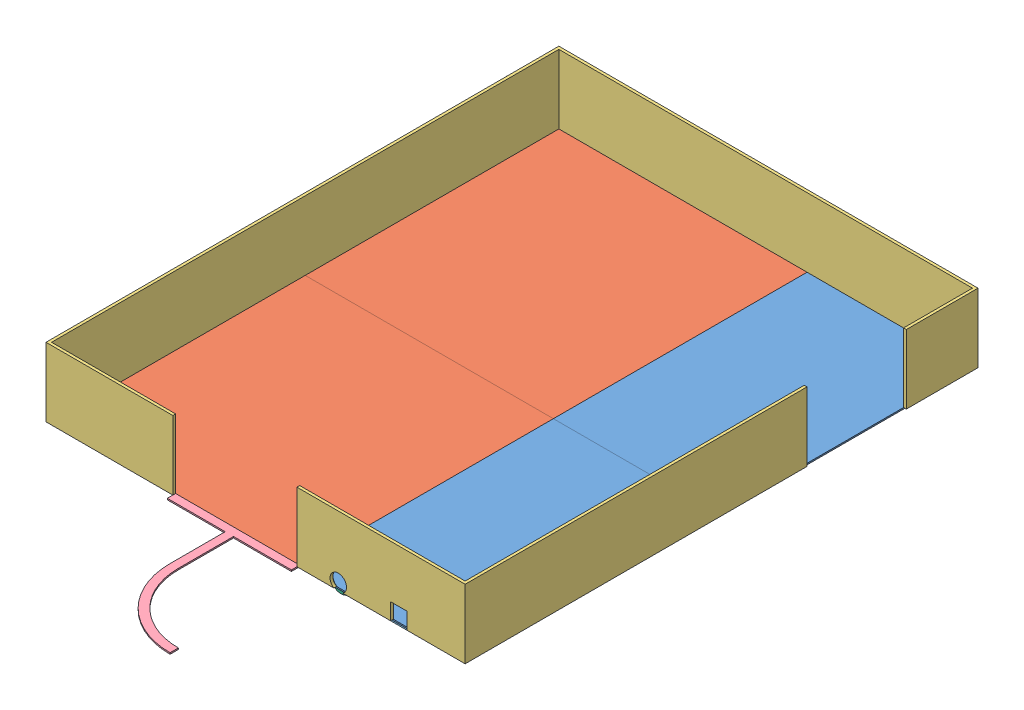
SolidWorks assembly Mosaic, configuration Default. Lengths in mm.
Overall size (1520 265 2360).
8 component instances, 6 part files, 20 mates.
Components (placement in the parent):
- Part2-1: Part2 [Default] at (315.7392 -5 1155.4589) size (600 5 920)
- Part2-2: Part2 [Default] at (315.7392 -5 2075.4589) size (600 5 920)
- Part2^Mosaic-1: Part2^Mosaic [Default] at (1396.6621 -5 82.6242) size (900 5 920) (virtual)
- Part2^Mosaic-2: Part2^Mosaic [Default] at (1396.6621 -5 -837.3758) size (900 5 920) (virtual)
- Part3^Mosaic-1: Part3^Mosaic [Default] at origin size (1520 250 1860) (virtual)
- Part4^Mosaic-1: Part4^Mosaic [Default] at (122.0061 -5 -12.8331) size (490 5 510) (virtual)
- Part5^Mosaic-1: Part5^Mosaic [Default] at (826.4444 -42.7357 2074.4589) x (1 0 0) z (0 -1 0) size (80 1 80) (virtual)
- Part6^Mosaic-1: Part6^Mosaic [Default] at (601.2126 136.7324 2074.4589) x (1 0 0) z (0 -1 0) size (80 1 80) (virtual)
Mates (geometry in assembly coordinates):
- Coincident1: coincident anti-aligned: plane of Part2-1 through (315.7392 0 1155.4589) normal (0 0 1); plane of Part2-2 through (315.7392 0 1155.4589) normal (0 0 -1)
- Coincident2: coincident aligned: plane of Part2-1 through (315.7392 -5 1155.4589) normal (0 -1 0); plane of Part2-2 through (315.7392 -5 2075.4589) normal (0 -1 0)
- Coincident3: coincident aligned: plane of Part2-1 through (315.7392 0 1155.4589) normal (-1 0 0); plane of Part2-2 through (315.7392 0 2075.4589) normal (-1 0 0)
- Coincident4: coincident anti-aligned: plane of Part2-2 through (315.7392 0 2075.4589) normal (-1 0 0); plane of Part2^Mosaic-1 through (315.7392 0 1155.4589) normal (1 0 0)
- Coincident5: coincident aligned: plane of Part2-2 through (315.7392 0 2075.4589) normal (0 1 0); plane of Part2^Mosaic-1 through (1396.6621 0 82.6242) normal (0 1 0)
- Coincident6: coincident aligned: plane of Part2-2 through (315.7392 0 2075.4589) normal (0 0 1); plane of Part2^Mosaic-1 through (-584.2608 0 2075.4589) normal (0 0 1)
- Coincident7: coincident anti-aligned: plane of Part2-1 through (315.7392 0 1155.4589) normal (-1 0 0); plane of Part2^Mosaic-2 through (315.7392 0 235.4589) normal (1 0 0)
- Coincident8: coincident aligned: plane of Part2-1 through (315.7392 0 1155.4589) normal (0 1 0); plane of Part2^Mosaic-2 through (1396.6621 0 -837.3758) normal (0 1 0)
- Coincident10: coincident anti-aligned: plane of Part2^Mosaic-1 through (-584.2608 0 1155.4589) normal (0 0 -1); plane of Part2^Mosaic-2 through (-584.2608 0 1155.4589) normal (0 0 1)
- Coincident11: coincident anti-aligned: plane of Part2^Mosaic-1 through (1396.6621 0 82.6242) normal (0 1 0); plane of Part3^Mosaic-1 through (0 0 0) normal (0 -1 0)
- Coincident17: coincident anti-aligned: plane of Part2^Mosaic-1 through (-584.2608 0 2075.4589) normal (0 0 1); plane of Part3^Mosaic-1 through (-134.2608 250 2075.4589) normal (0 0 -1)
- Coincident18: coincident anti-aligned: plane of Part2^Mosaic-1 through (-584.2608 0 1155.4589) normal (-1 0 0); plane of Part3^Mosaic-1 through (-584.2608 250 235.4589) normal (1 0 0)
- Coincident20: coincident aligned: plane of Part2^Mosaic-1 through (1396.6621 -5 82.6242) normal (0 -1 0); plane of Part4^Mosaic-1 through (355.7392 -5 2305.4589) normal (0 -1 0)
- Coincident23: coincident anti-aligned: plane of Part2^Mosaic-1 through (-584.2608 0 2075.4589) normal (0 0 1); plane of Part4^Mosaic-1 through (315.7392 0 2075.4589) normal (0 0 -1)
- Coincident24: coincident anti-aligned: plane of Part3^Mosaic-1 through (-134.2608 250 2085.4589) normal (1 0 0); plane of Part4^Mosaic-1 through (-134.2608 0 2075.4589) normal (-1 0 0)
- Coincident26: coincident anti-aligned: plane of Part3^Mosaic-1 through (915.7392 250 2075.4589) normal (0 0 -1); plane of Part5^Mosaic-1 through (826.4444 -42.7357 2075.4589) normal (0 0 1)
- Coincident27: coincident aligned: plane of Part3^Mosaic-1 through (715.7392 0 2085.4599) normal (-1 0 0); plane of Part5^Mosaic-1 through (715.7392 60 2075.4589) normal (-1 0 0)
- Coincident28: coincident aligned: plane of Part3^Mosaic-1 through (715.7392 60 2085.4599) normal (0 -1 0); plane of Part5^Mosaic-1 through (655.7392 60 2075.4589) normal (0 -1 0)
- Coincident29: coincident: plane of Part3^Mosaic-1 through (915.7392 250 2075.4589) normal (0 0 -1); plane of Part6^Mosaic-1 through (465.7392 25 2075.4589) normal (0 0 1)
- Concentric1: concentric aligned: cylinder of Part3^Mosaic-1 through (465.7392 25 2085.4599) axis (0 0 -1) radius 30; cylinder of Part6^Mosaic-1 through (465.7392 25 2075.4589) axis (0 0 -1) radius 30
